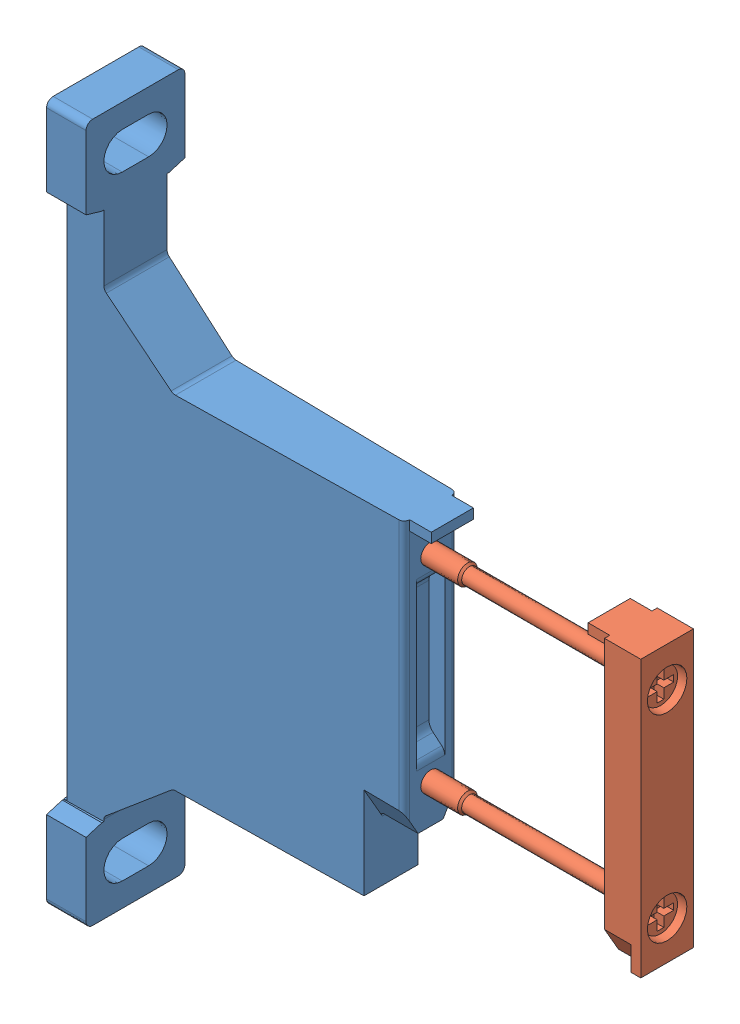
SolidWorks assembly 526063 MS4-WPB, configuration Default. Lengths in mm.
Overall size (58.1 126.95 40).
2 component instances, 2 part files, 0 mates.
Components (placement in the parent):
- 526063 MS4-WPB---(wp)-1: 526063 MS4-WPB---(wp) [Default] at origin size (54.1 106 15)
- 532798 MS4-MV---(ms4)-1: 532798 MS4-MV---(ms4) [Default] at (81.2 38.1 0) x (0 0 1) z (-1 0 0) size (8 41.9 40)
